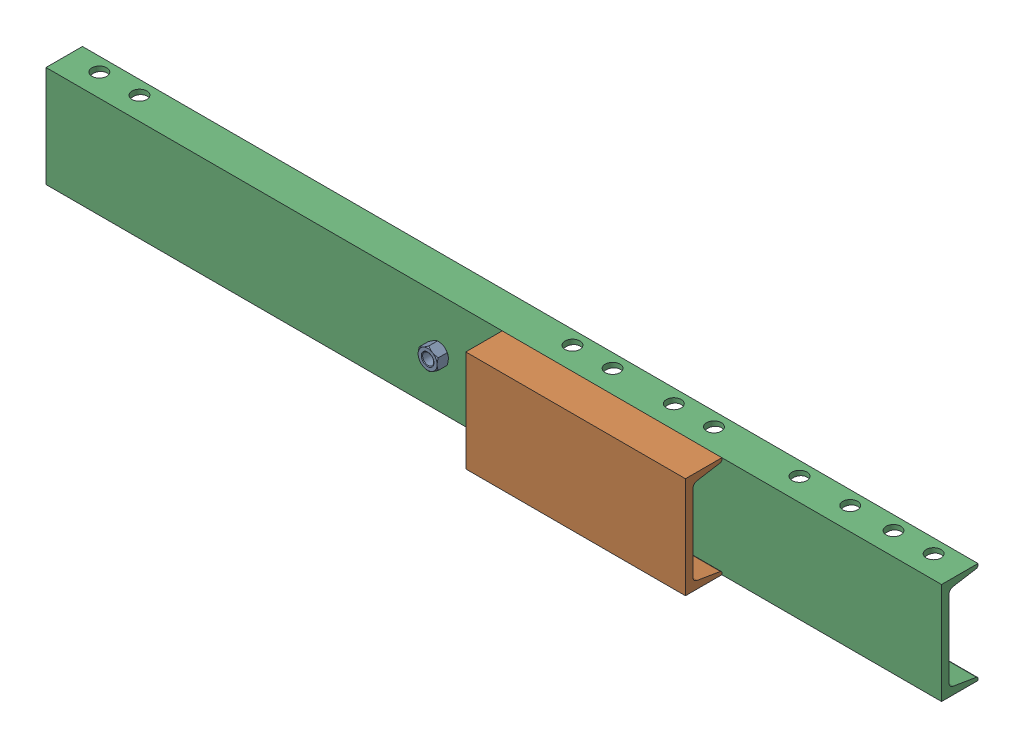
SolidWorks assembly 01-114-00-0, configuration Default. Lengths in mm.
Overall size (1346.2 152.4 109.58).
3 component instances, 3 part files, 0 mates.
Components (placement in the parent):
- hex nut_ai(HNUT 0.7500-10-D-C)-1: hex nut_ai(HNUT 0.7500-10-D-C) [Default] at (-82.55 0 44.2849) size (28.57 33 16.89)
- 01-034-00-0-1: 01-034-00-0 [Default] at (177.8 0 54.7878) size (330.2 152.4 54.79)
- 01-015-00-0-1: 01-015-00-0 [Default] at origin size (1346.2 152.4 54.79)
